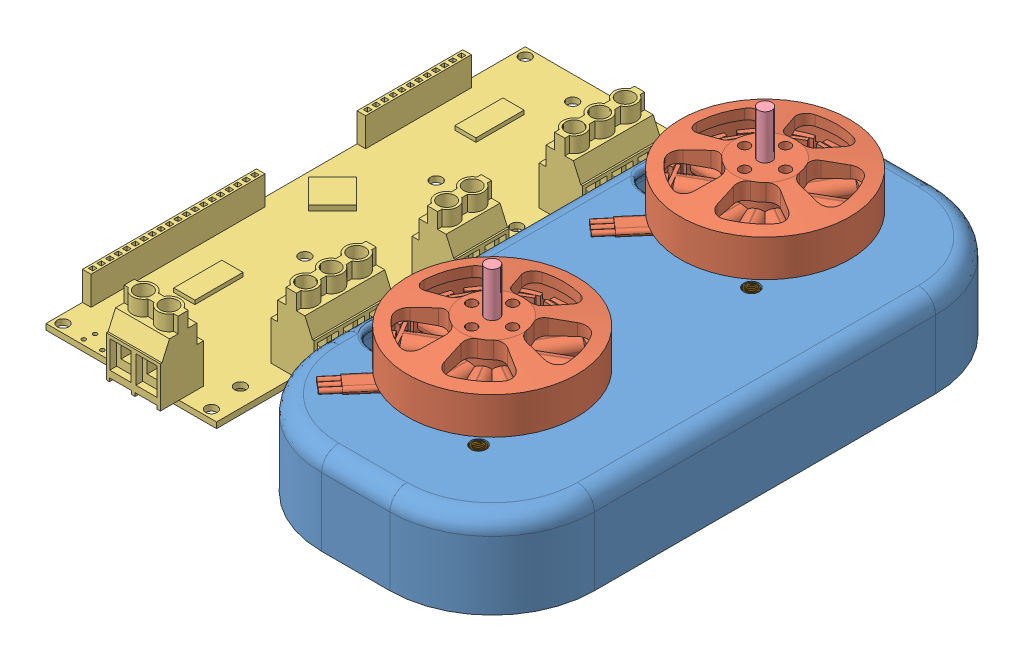
SolidWorks assembly TEST_BENCH, configuration Default. Lengths in mm.
Overall size (142.43 64.39 160).
66 component instances, 27 part files, 15 mates.
Components (placement in the parent):
- MOTOR_FRAME-1: MOTOR_FRAME [Default] at (20.3364 38.6086 42.1845) size (80 25 160)
- BLDC_Motor_5010-1: BLDC_Motor_5010 [Varsayılan] at (20.3364 38.6086 42.1845) size (50.08 20 54.53)
- Motor driver ODRIVE V3.6.stp-1: Motor driver ODRIVE V3.6.stp [Default] at (-57.0922 36.4406 0.3093) x (0 0 -1) z (0 1 0) size (146 55.7 33.72)
- MOTOR_SHAFT-1: MOTOR_SHAFT [Default] at (20.3364 54.6086 42.1845) x (-0.711193 0 -0.702997) z (0.702997 0 -0.711193) size (4 34 4)
- socket countersunk head screw_din-4: socket countersunk head screw_din [DIN 7991 - M3 x 8 --- 4.8N] at (28.3364 36.5586 42.1845) x (0 1 0) z (-0.429429 0 0.903101) size (8 5.7 5.7)
- socket countersunk head screw_din-7: socket countersunk head screw_din [DIN 7991 - M3 x 8 --- 4.8N] at (20.3364 36.5586 34.1845) x (0 1 0) z (0.903101 0 0.429429) size (8 5.7 5.7)
- socket countersunk head screw_din-8: socket countersunk head screw_din [DIN 7991 - M3 x 8 --- 4.8N] at (12.3364 36.5586 42.1845) x (0 1 0) z (0.429429 0 -0.903101) size (8 5.7 5.7)
- socket countersunk head screw_din-9: socket countersunk head screw_din [DIN 7991 - M3 x 8 --- 4.8N] at (20.3364 36.5586 50.1845) x (0 1 0) z (-0.903101 0 -0.429429) size (8 5.7 5.7)
- Encoder_magnet-1: Encoder_magnet [Default] at (20.3364 36.1086 42.1845) x (-0.937731 0 -0.347361) z (0.347361 0 -0.937731) size (4 1.5 4)
- AS5048a Magnetic Encoder.step-1: AS5048a Magnetic Encoder.step [Default] at (18.8651 34.6086 39.587) x (1 0 0) z (0 1 0) size (15 17.37 2.2)
  - Component2.step-1: Component2.step [Default] at origin size (0.79 0.74 0.3)
  - Component6.step-1: Component6.step [Default] at origin size (0.79 0.36 0.28)
  - Component7.step-1: Component7.step [Default] at origin size (0.79 0.33 0.28)
  - Component10.step-1: Component10.step [Default] at origin size (0.36 2.99 0.05)
  - Component5.step-1: Component5.step [Default] at origin size (0.79 0.74 0.3)
  - Component9.step-1: Component9.step [Default] at origin size (0.79 0.33 0.28)
  - Component8.step-1: Component8.step [Default] at origin size (0.79 0.36 0.28)
  - Component4.step-1: Component4.step [Default] at origin size (0.36 2.99 0.05)
  - Component3.step-1: Component3.step [Default] at origin size (0.36 2.99 0.05)
  - Component17.step-1: Component17.step [Default] at origin size (5.39 6.68 1.2)
  - Component15.step-1: Component15.step [Default] at origin size (0.36 2.99 0.05)
  - Component14.step-1: Component14.step [Default] at origin size (0.39 2.99 0.05)
  - Component18.step-1: Component18.step [Default] at origin size (0.33 2.67 0.05)
  - Component19.step-1: Component19.step [Default] at origin size (1.7 2.63 0.05)
  - Component11.step-1: Component11.step [Default] at origin size (1.7 2.63 0.05)
  - Component12.step-1: Component12.step [Default] at origin size (0.33 2.99 0.05)
  - Component16.step-1: Component16.step [Default] at origin size (1.7 2.63 0.05)
  - Component13.step-1: Component13.step [Default] at origin size (0.35 2.67 0.05)
  - Magnetic Encoder.step-1: Magnetic Encoder.step [Default] at origin size (15 17.37 1)
- ENCODER_HOUSING_TEST_BENCH-1: ENCODER_HOUSING_TEST_BENCH [Default] at (20.3364 33.1086 42.1845) x (-1 0 0) z (0 0 -1) size (29 1.5 37)
- Encoder_magnet-4: Encoder_magnet [Default] at (20.3364 36.1086 -37.8155) x (-0.937731 0 -0.347361) z (0.347361 0 -0.937731) size (4 1.5 4)
- AS5048a Magnetic Encoder.step-2: AS5048a Magnetic Encoder.step [Default] at (18.8651 34.6086 -40.413) x (1 0 0) z (0 1 0) size (15 17.37 2.2)
  - Component2.step-1: Component2.step [Default] at origin size (0.79 0.74 0.3)
  - Component6.step-1: Component6.step [Default] at origin size (0.79 0.36 0.28)
  - Component7.step-1: Component7.step [Default] at origin size (0.79 0.33 0.28)
  - Component10.step-1: Component10.step [Default] at origin size (0.36 2.99 0.05)
  - Component5.step-1: Component5.step [Default] at origin size (0.79 0.74 0.3)
  - Component9.step-1: Component9.step [Default] at origin size (0.79 0.33 0.28)
  - Component8.step-1: Component8.step [Default] at origin size (0.79 0.36 0.28)
  - Component4.step-1: Component4.step [Default] at origin size (0.36 2.99 0.05)
  - Component3.step-1: Component3.step [Default] at origin size (0.36 2.99 0.05)
  - Component17.step-1: Component17.step [Default] at origin size (5.39 6.68 1.2)
  - Component15.step-1: Component15.step [Default] at origin size (0.36 2.99 0.05)
  - Component14.step-1: Component14.step [Default] at origin size (0.39 2.99 0.05)
  - Component18.step-1: Component18.step [Default] at origin size (0.33 2.67 0.05)
  - Component19.step-1: Component19.step [Default] at origin size (1.7 2.63 0.05)
  - Component11.step-1: Component11.step [Default] at origin size (1.7 2.63 0.05)
  - Component12.step-1: Component12.step [Default] at origin size (0.33 2.99 0.05)
  - Component16.step-1: Component16.step [Default] at origin size (1.7 2.63 0.05)
  - Component13.step-1: Component13.step [Default] at origin size (0.35 2.67 0.05)
  - Magnetic Encoder.step-1: Magnetic Encoder.step [Default] at origin size (15 17.37 1)
- MOTOR_SHAFT-4: MOTOR_SHAFT [Default] at (20.3364 54.6086 -37.8155) x (-0.711193 0 -0.702997) z (0.702997 0 -0.711193) size (4 34 4)
- socket countersunk head screw_din-24: socket countersunk head screw_din [DIN 7991 - M3 x 8 --- 4.8N] at (12.3364 36.5586 -37.8155) x (0 1 0) z (0.429429 0 -0.903101) size (8 5.7 5.7)
- socket countersunk head screw_din-25: socket countersunk head screw_din [DIN 7991 - M3 x 8 --- 4.8N] at (20.3364 36.5586 -45.8155) x (0 1 0) z (0.903101 0 0.429429) size (8 5.7 5.7)
- socket countersunk head screw_din-26: socket countersunk head screw_din [DIN 7991 - M3 x 8 --- 4.8N] at (20.3364 36.5586 -29.8155) x (0 1 0) z (-0.903101 0 -0.429429) size (8 5.7 5.7)
- socket countersunk head screw_din-27: socket countersunk head screw_din [DIN 7991 - M3 x 8 --- 4.8N] at (28.3364 36.5586 -37.8155) x (0 1 0) z (-0.429429 0 0.903101) size (8 5.7 5.7)
- BLDC_Motor_5010-4: BLDC_Motor_5010 [Varsayılan] at (20.3364 38.6086 -37.8155) size (50.08 20 54.53)
- ENCODER_HOUSING_TEST_BENCH-2: ENCODER_HOUSING_TEST_BENCH [Default] at (20.3364 33.1086 -37.8155) x (-1 0 0) z (0 0 -1) size (29 1.5 37)
- M3_INSERT.step-1: M3_INSERT.step [Default] at (9.3364 34.6086 27.1845) size (4.52 4 4.53)
- M3_INSERT.step-2: M3_INSERT.step [Default] at (31.3364 34.6086 27.1845) size (4.52 4 4.53)
- M3_INSERT.step-3: M3_INSERT.step [Default] at (31.3364 34.6086 57.1845) size (4.52 4 4.53)
- M3_INSERT.step-4: M3_INSERT.step [Default] at (9.3364 34.6086 57.1845) size (4.52 4 4.53)
- M3_INSERT.step-5: M3_INSERT.step [Default] at (9.3364 34.6086 -52.8155) size (4.52 4 4.53)
- M3_INSERT.step-6: M3_INSERT.step [Default] at (31.3364 34.6086 -52.8155) size (4.52 4 4.53)
- M3_INSERT.step-7: M3_INSERT.step [Default] at (31.3364 34.6086 -22.8155) size (4.52 4 4.53)
- M3_INSERT.step-8: M3_INSERT.step [Default] at (9.3364 34.6086 -22.8155) size (4.52 4 4.53)
Mates (geometry in assembly coordinates):
- Concentric2: concentric aligned: cylinder of MOTOR_FRAME-1 through (20.3364 36.6086 34.1845) axis (0 -1 0) radius 1.7; cylinder of BLDC_Motor_5010-1 through (20.3364 42.1086 34.1845) axis (0 -1 0) radius 1.5
- Coincident2: coincident anti-aligned: plane of MOTOR_FRAME-1 through (20.3364 38.6086 42.1845) normal (0 1 0); plane of BLDC_Motor_5010-1 through (20.3364 38.6086 42.1845) normal (0 -1 0)
- Concentric3: concentric anti-aligned: cylinder of BLDC_Motor_5010-1 through (20.3364 38.6086 42.1845) axis (0 1 0) radius 2; cylinder of MOTOR_SHAFT-1 through (20.3364 71.6086 42.1845) axis (0 -1 0) radius 2
- Concentric4: concentric aligned: cylinder of MOTOR_FRAME-1 through (20.3364 36.6086 50.1845) axis (0 -1 0) radius 1.7; cylinder of BLDC_Motor_5010-1 through (20.3364 42.1086 50.1845) axis (0 -1 0) radius 1.5
- Distance1: distance = 1 mm aligned: plane of BLDC_Motor_5010-1 through (20.3364 38.6086 42.1845) normal (0 -1 0); plane of MOTOR_SHAFT-1 through (20.3364 37.6086 42.1845) normal (0 -1 0)
- Concentric17: concentric aligned: cylinder of BLDC_Motor_5010-1 through (28.3364 42.1086 42.1845) axis (0 -1 0) radius 1.5; cylinder of M3x5_socket_head_screw-4 through (28.3364 36.5586 42.1845) axis (0 -1 0) radius 1.5
- Coincident16: coincident aligned: cone of MOTOR_FRAME-1 through (28.3364 36.6086 42.1845) axis (0 1 0); cone of M3x5_socket_head_screw-4 through (28.3364 36.9086 42.1845) axis (0 1 0)
- Concentric18: concentric aligned: cylinder of MOTOR_SHAFT-1 through (20.3364 71.6086 42.1845) axis (0 -1 0) radius 2; cylinder of Encoder_magnet-1 through (20.3364 37.6086 42.1845) axis (0 -1 0) radius 2
- Coincident17: coincident anti-aligned: plane of MOTOR_SHAFT-1 through (20.3364 37.6086 42.1845) normal (0 -1 0); plane of Encoder_magnet-1 through (20.3364 37.6086 42.1845) normal (0 1 0)
- Coincident23: coincident anti-aligned: plane of AS5048a Magnetic Encoder.step-1/Magnetic Encoder.step-1 through (20.2684 33.6086 42.8746) normal (0 -1 0); plane of ENCODER_HOUSING_TEST_BENCH-1 through (20.3364 33.6086 42.1845) normal (0 1 0)
- Concentric20: concentric anti-aligned: cylinder of AS5048a Magnetic Encoder.step-1/Magnetic Encoder.step-1 through (26.3614 34.6086 42.1845) axis (0 -1 0) radius 1.0975; cylinder of ENCODER_HOUSING_TEST_BENCH-1 through (26.3614 33.1086 42.1845) axis (0 1 0) radius 1.095
- Parallel2: parallel anti-aligned: plane of AS5048a Magnetic Encoder.step-1/Magnetic Encoder.step-1 through (16.0915 34.6086 34.188) normal (0 0 -1); plane of ENCODER_HOUSING_TEST_BENCH-1 through (20.3364 34.6086 33.688) normal (0 0 1)
- Coincident25: coincident aligned: plane of MOTOR_FRAME-1 through (27.8364 34.6086 23.6845) normal (0 0 -1); plane of ENCODER_HOUSING_TEST_BENCH-1 through (5.8364 33.6086 23.6845) normal (0 0 -1)
- Coincident26: coincident aligned: plane of MOTOR_FRAME-1 through (34.8364 34.6086 23.6845) normal (1 0 0); plane of ENCODER_HOUSING_TEST_BENCH-1 through (34.8364 33.6086 23.6845) normal (1 0 0)
- Coincident32: coincident anti-aligned: plane of MOTOR_FRAME-1 through (20.3364 34.6086 42.1845) normal (0 -1 0); plane of ENCODER_HOUSING_TEST_BENCH-1 through (20.3364 34.6086 42.1845) normal (0 1 0)
